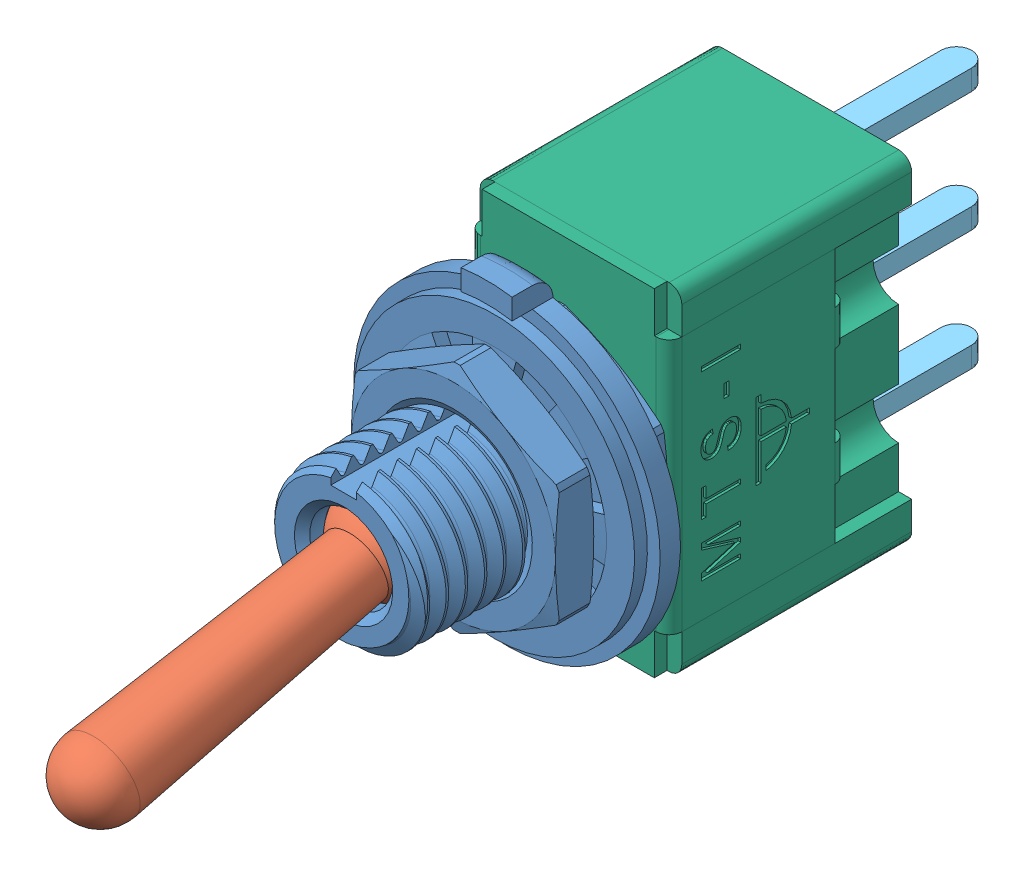
SolidWorks assembly MTS-1xx-A2-blue-OFF.step, configuration Default. Lengths in mm.
Overall size (12 13.4 35.63).
6 component instances, 6 part files, 0 mates.
Components (placement in the parent):
- eBom-prt0.step-1: eBom-prt0.step [Default] at (0 0 10.3) x (1 0 0) z (0 1 0) size (12 9.99 12.8)
- Handle.step-1: Handle.step [Default] at (0 0 19.1) x (-1 0 0) z (0 -1 0) size (3.8 17.38 5.93)
- eBom-prt2.step-1: eBom-prt2.step [Default] at (0 0 4.4) x (-1 0 0) z (0 -1 0) size (3.55 1.36 10.22)
- L.step-1: L.step [Default] at (0 -0.1062 17.6994) x (1 0 0) z (0 0.978148 0.207912) size (3.55 20.58 3.55)
- eBom-prt4.step-1: eBom-prt4.step [Default] at (0 0 4.4) size (3.7 10.2 9.9)
- Housing.step-1: Housing.step [Default] at (0 0 10.3) x (1 0 0) z (0 1 0) size (7.9 10.3 13.2)
